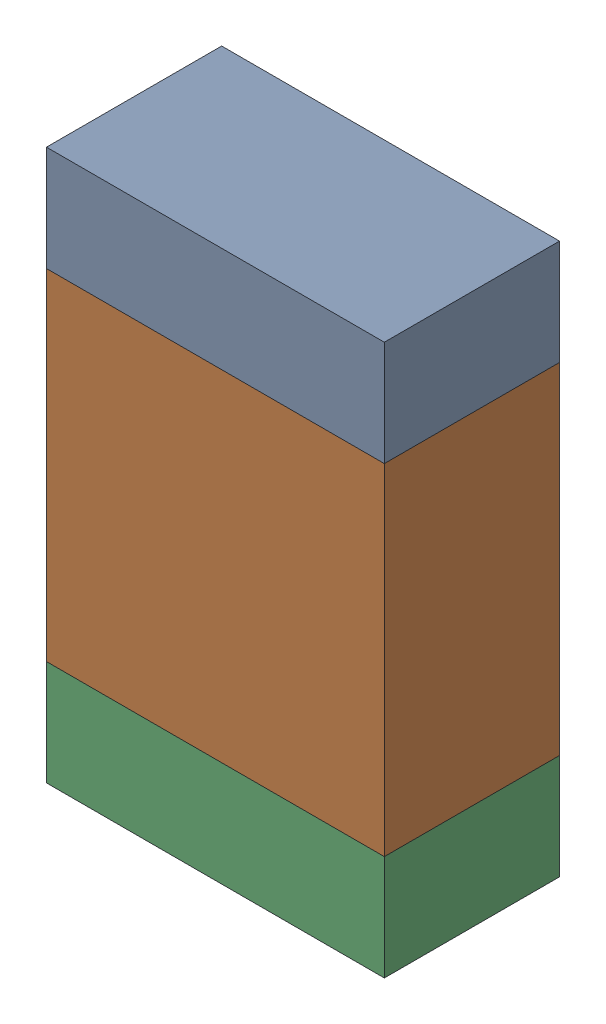
SolidWorks assembly R14, configuration Default. Lengths in mm.
Overall size (1.35 2.2 0.7).
6 component instances, 2 part files, 0 mates.
Components (placement in the parent):
- 959207304-1: 959207304 [Default] at (110.6132 93.495 0) size (1.35 0.42 0.7)
  - Extruded-8-1: Extruded-8 [Default] at origin size (1.35 0.42 0.7)
- 959207440-1: 959207440 [Default] at (110.6132 92.605 0) size (1.35 1.36 0.7)
  - Extruded-9-1: Extruded-9 [Default] at origin size (1.35 1.36 0.7)
- 959207304-2: 959207304 [Default] at (110.6132 91.715 0) size (1.35 0.42 0.7)
  - Extruded-8-1: Extruded-8 [Default] at origin size (1.35 0.42 0.7)
